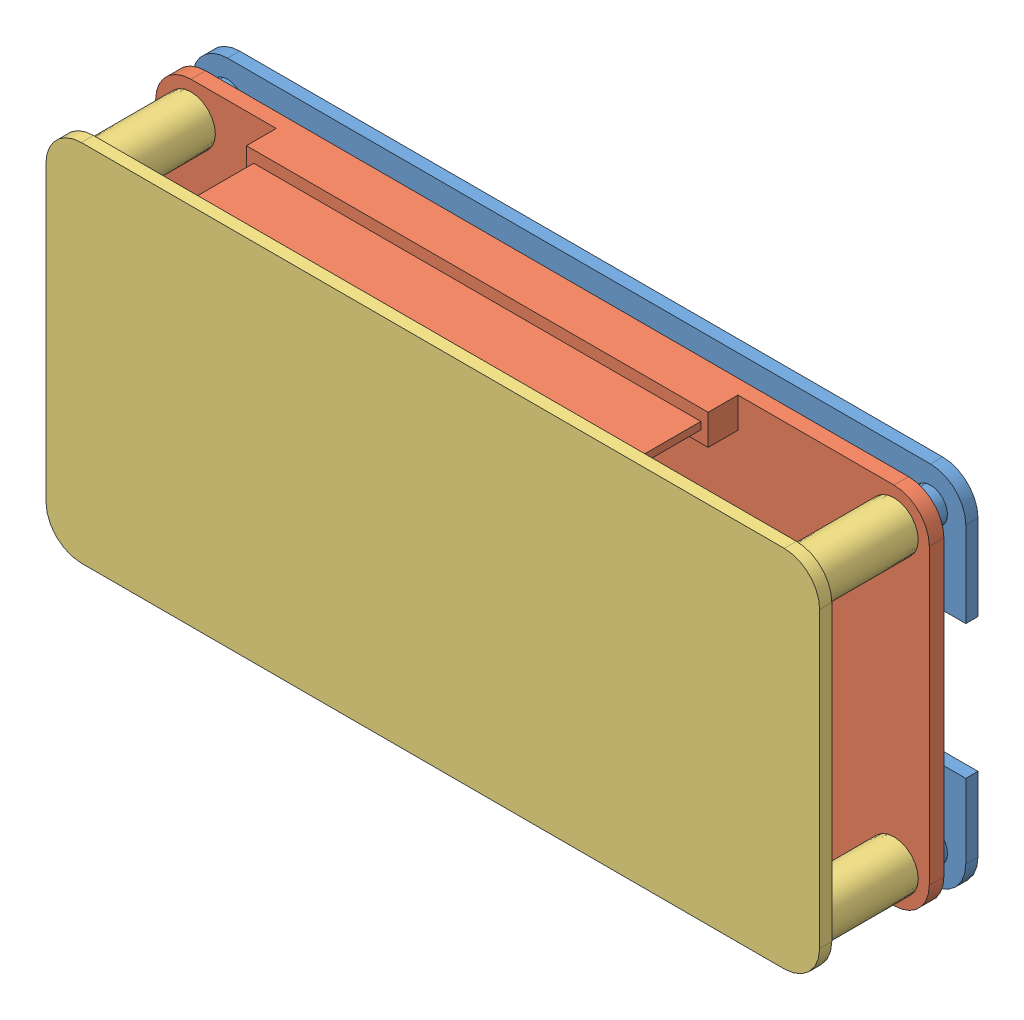
SolidWorks assembly 装配体1, configuration 默认. Lengths in mm.
Overall size (63.5 29.9 13.25).
3 component instances, 3 part files, 6 mates.
Components (placement in the parent):
- 外壳-1: 外壳 [默认] at (-37.1639 -8.0547 78) size (63.5 29.9 12)
- ESP32-1: ESP32 [默认] at (20.5361 16.0453 80.8) x (-1 0 0) z (0 0 1) size (63.5 29.9 12.2)
- 底座-1: 底座 [默认] at (20.5361 -8.0547 91) x (-1 0 0) z (0 0 -1) size (63.5 29.9 9)
Mates (geometry in assembly coordinates):
- 同心5: concentric: circle of ESP32-1; circle of 外壳-1
- 同心4: concentric: circle of ESP32-1; circle of 外壳-1
- 重合6: coincident anti-aligned: plane of 外壳-1 through (20.5361 16.0453 90) normal (0 0 1); plane of 底座-1 through (20.5361 -8.0547 90) normal (0 0 -1)
- 同心6: concentric anti-aligned: circle of 外壳-1; circle of 底座-1
- 同心7: concentric anti-aligned: circle of 外壳-1; circle of 底座-1
- 重合7: coincident anti-aligned: plane of ESP32-1 through (20.5361 16.0453 82) normal (0 0 1); plane of 底座-1 through (-37.1639 -8.0547 82) normal (0 0 -1)
